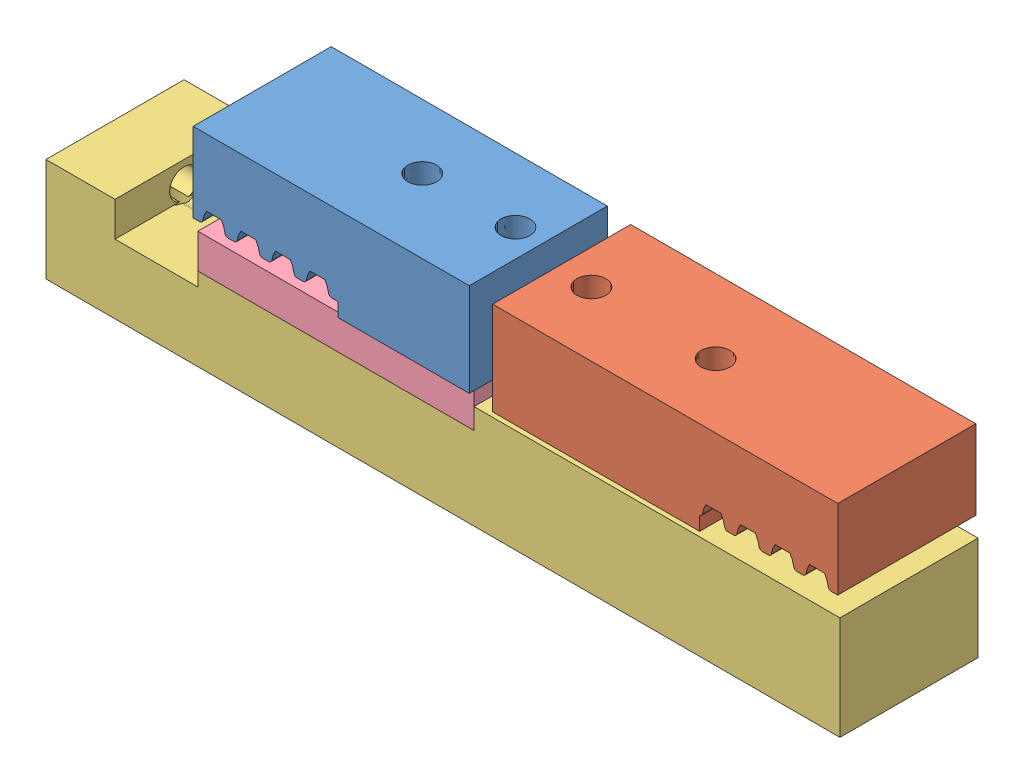
SolidWorks assembly 皮带连接左右, configuration 默认. Lengths in mm.
Overall size (115 30.5 21.37).
4 component instances, 4 part files, 9 mates.
Components (placement in the parent):
- 皮带夹S5M-40-1: 皮带夹S5M-40 [默认] at (4.7411 4.7818 11.9995) x (0 0 1) z (1 0 0) size (20 13.5 40)
- 皮带夹S5M-50-1: 皮带夹S5M-50 [默认] at (30.7411 2.7818 3.6259) x (0 0 -1) z (-1 0 0) size (20 13.5 50)
- 皮带连接块115-1: 皮带连接块115 [默认] at (7.2411 -0.1182 -2.1873) size (115 15 20)
- 皮带连接块40-1: 皮带连接块40 [默认] at (-8.2589 4.3818 7.8127) size (40 5 20)
Mates (geometry in assembly coordinates):
- 重合1: coincident anti-aligned: plane of 复件 复件 复件 复件 _ECY11-S5M100-C                                100 S5M^装配体1_过道-1 through (30.7411 7.3818 3.6259) normal (0 -1 0); plane of 皮带连接块-1 through (-50.2589 7.3818 17.8127) normal (0 1 0)
- 同心1: concentric anti-aligned: circle of 皮带夹S5M-50-1; circle of 皮带连接块115-1
- 平行1: parallel aligned: plane of 复件 复件 复件 复件 _ECY11-S5M100-C                                100 S5M^装配体1_过道-1 through (-2.1674 9.8818 17.1259) normal (0 0 1); plane of 皮带连接块-1 through (7.2411 -0.1182 17.8127) normal (0 0 1)
- 重合3: coincident anti-aligned: plane of 皮带连接块-1 through (7.2411 4.3818 -2.1873) normal (0 1 0); plane of 复件 零件7^装配体1_过道-1 through (-8.2589 4.3818 7.8127) normal (0 -1 0)
- 重合4: coincident anti-aligned: plane of 皮带连接块-1 through (11.7411 4.3818 -2.1873) normal (-1 0 0); plane of 复件 零件7^装配体1_过道-1 through (11.7411 9.3818 -2.1873) normal (1 0 0)
- 重合5: coincident aligned: plane of 皮带连接块-1 through (7.2411 -0.1182 17.8127) normal (0 0 1); plane of 复件 零件7^装配体1_过道-1 through (-28.2589 9.3818 17.8127) normal (0 0 1)
- 重合6: coincident anti-aligned: plane of 复件 复件 复件 _ECY11-S5M100-C                                100 S5M^装配体1_过道-1 through (4.7411 9.3818 11.9995) normal (0 -1 0); plane of 复件 零件7^装配体1_过道-1 through (-8.2589 9.3818 7.8127) normal (0 1 0)
- 同心4: concentric aligned: circle of 复件 复件 复件 _ECY11-S5M100-C                                100 S5M^装配体1_过道-1; circle of 复件 零件7^装配体1_过道-1
- 平行2: parallel aligned: plane of 复件 复件 复件 _ECY11-S5M100-C                                100 S5M^装配体1_过道-1 through (37.6496 11.8818 18.4995) normal (0 0 1); plane of 复件 零件7^装配体1_过道-1 through (-28.2589 9.3818 17.8127) normal (0 0 1)
